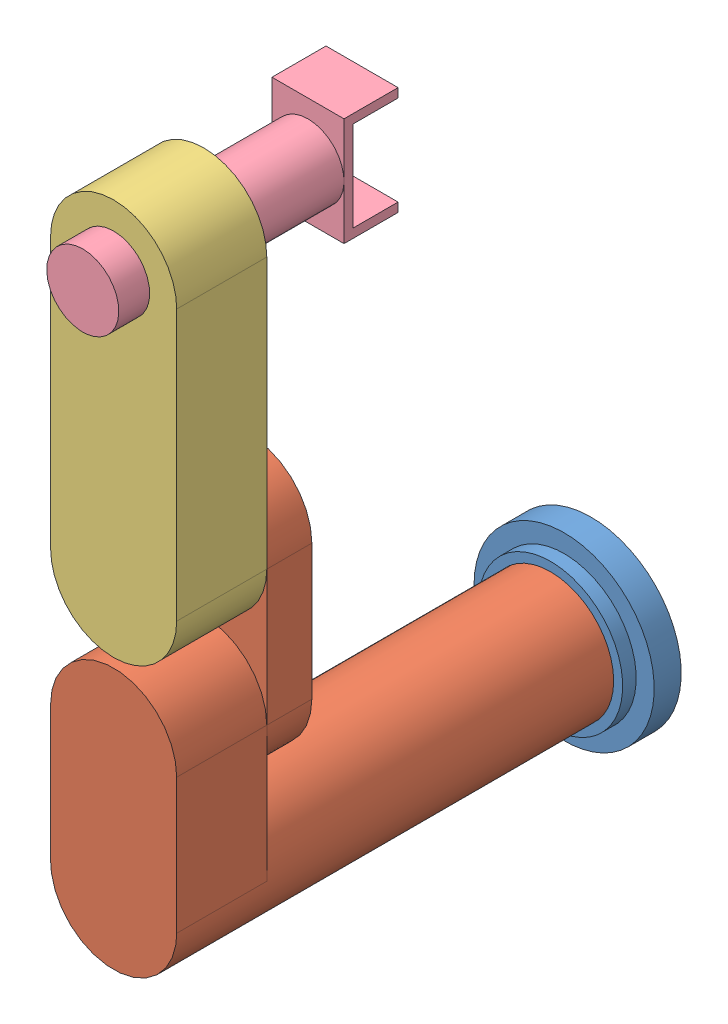
SolidWorks assembly SCARA, configuration Domyślna. Lengths in mm.
Overall size (200 770 564.28).
4 component instances, 4 part files, 8 mates.
Components (placement in the parent):
- C0-1: C0 [Domyślna] at (-6.7839 15.164 200) size (200 200 45)
- C1-1: C1 [Domyślna] at (-6.7839 15.164 230) x (0 -1 0) z (0 0 1) size (440 140 500)
- C2-1: C2 [Domyślna] at (-6.7839 315.164 630) x (0 1 0) z (0 0 1) size (457.46 140 156.47)
- C3-1: C3 [Domyślna] at (-6.7839 615.164 764.2791) x (0 -1 0) z (0 0 -1) size (120 80 310)
Mates (geometry in assembly coordinates):
- Wspólnie1: coincident anti-aligned: plane of C0-1 through (-6.7839 15.164 230) normal (0 0 1); plane of C1-1 through (-6.7839 15.164 230) normal (0 0 -1)
- Koncentryczne1: concentric aligned: cylinder of C0-1 through (-6.7839 15.164 245) axis (0 0 -1) radius 70; cylinder of C1-1 through (-6.7839 15.164 630) axis (0 0 -1) radius 70
- Wspólnie4: coincident anti-aligned: plane of C1-1 through (-6.7839 165.164 630) normal (0 0 1); plane of C2-1 through (-6.7839 315.164 630) normal (0 0 -1)
- Koncentryczne2: concentric anti-aligned: circle of C1-1; circle of C2-1
- Koncentryczne3: concentric anti-aligned: circle of C2-1; circle of C3-1
- Równolegle1: parallel anti-aligned: plane of C2-1 through (-76.7839 315.164 730) normal (-1 0 0)
- Równolegle2: parallel anti-aligned: plane of C3-1 through (-46.7839 555.164 504.2791) normal (-1 0 0)
- Równolegle3: parallel anti-aligned: plane of C1-1 through (-76.7839 15.164 730) normal (-1 0 0)
